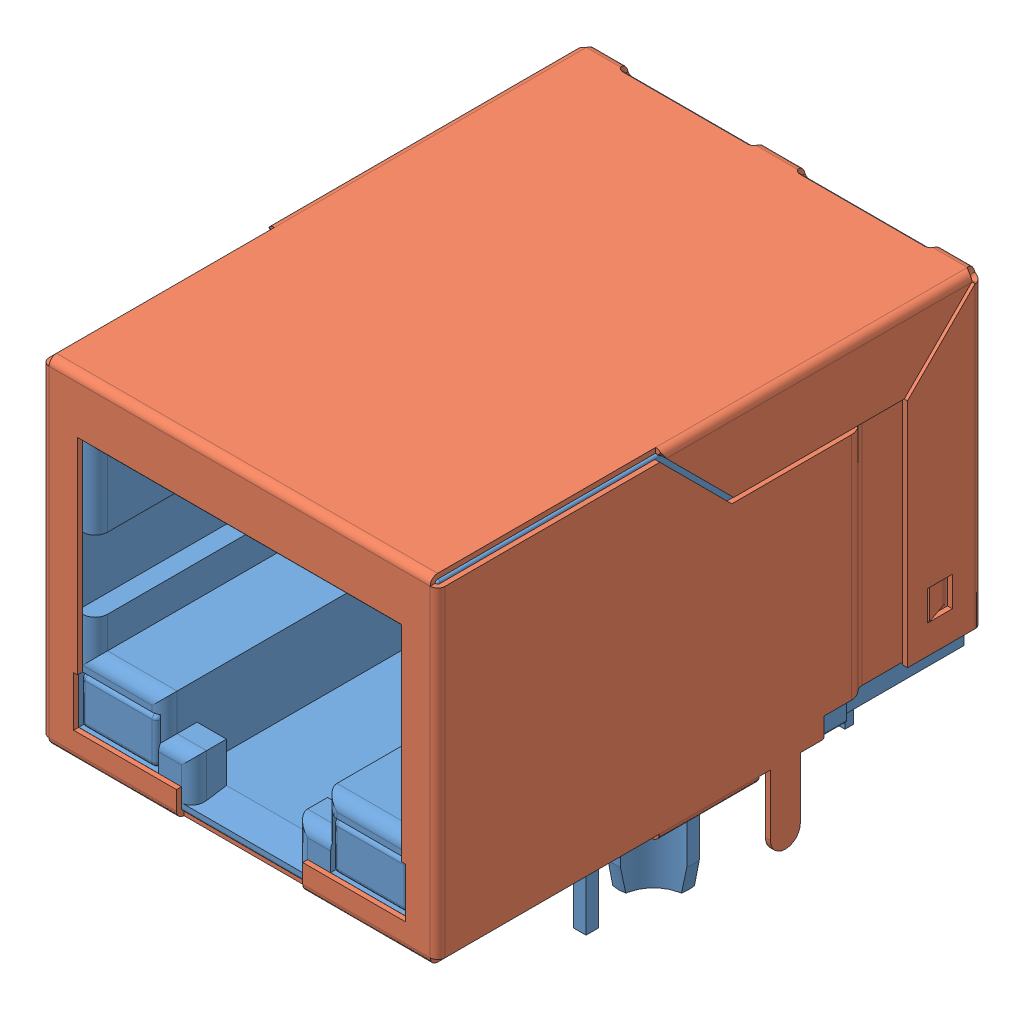
SolidWorks assembly LPJ0011BBNL - RJ45, configuration Default. Lengths in mm.
Overall size (15.88 16.55 21.84).
2 component instances, 2 part files, 6 mates.
Components (placement in the parent):
- LINK LP0011BBNL Internal-1: LINK LP0011BBNL Internal [Default] x (-1 0 0) z (0 0 1) size (15.48 16.35 21.44)
- LINK LP0011BBNL-1: LINK LP0011BBNL [Default] at (0 0 0.03) x (-1 0 0) z (0 -1 0) size (15.88 21.84 16.25)
Mates (geometry in assembly coordinates):
- Coincident1: coincident: plane of LINK LP0011BBNL Internal-1; plane of assembly through (0 0 0) normal (0 1 0)
- Coincident2: coincident: plane of LINK LP0011BBNL Internal-1; plane of assembly through (0 0 0) normal (1 0 0)
- Coincident3: coincident: plane of LINK LP0011BBNL Internal-1 through (0 0 0) normal (0 0 1); plane of assembly through (0 0 0) normal (0 0 1)
- Width1: width: plane of LINK LP0011BBNL-1 through (-7.74 -6.45 10.7504) normal (1 0 0); plane of LINK LP0011BBNL-1 through (7.74 6.45 10.7504) normal (-1 0 0); plane of LINK LP0011BBNL Internal-1 through (-7.74 -6.55 10.72) normal (-1 0 0); plane of LINK LP0011BBNL Internal-1 through (7.74 -6.55 10.72) normal (1 0 0)
- Width2: width: plane of LINK LP0011BBNL-1 through (7.64 -6.75 10.72) normal (0 0 -1); plane of LINK LP0011BBNL-1 through (7.64 6.75 -10.72) normal (0 0 1); plane of LINK LP0011BBNL Internal-1 through (0 0 10.72) normal (0 0 1); plane of LINK LP0011BBNL Internal-1 through (0 0 -10.72) normal (0 0 -1)
- Coincident4: coincident: plane of LINK LP0011BBNL Internal-1 through (7.74 6.55 10.72) normal (0 1 0); plane of LINK LP0011BBNL-1 through (7.64 6.55 10.92) normal (0 -1 0)
